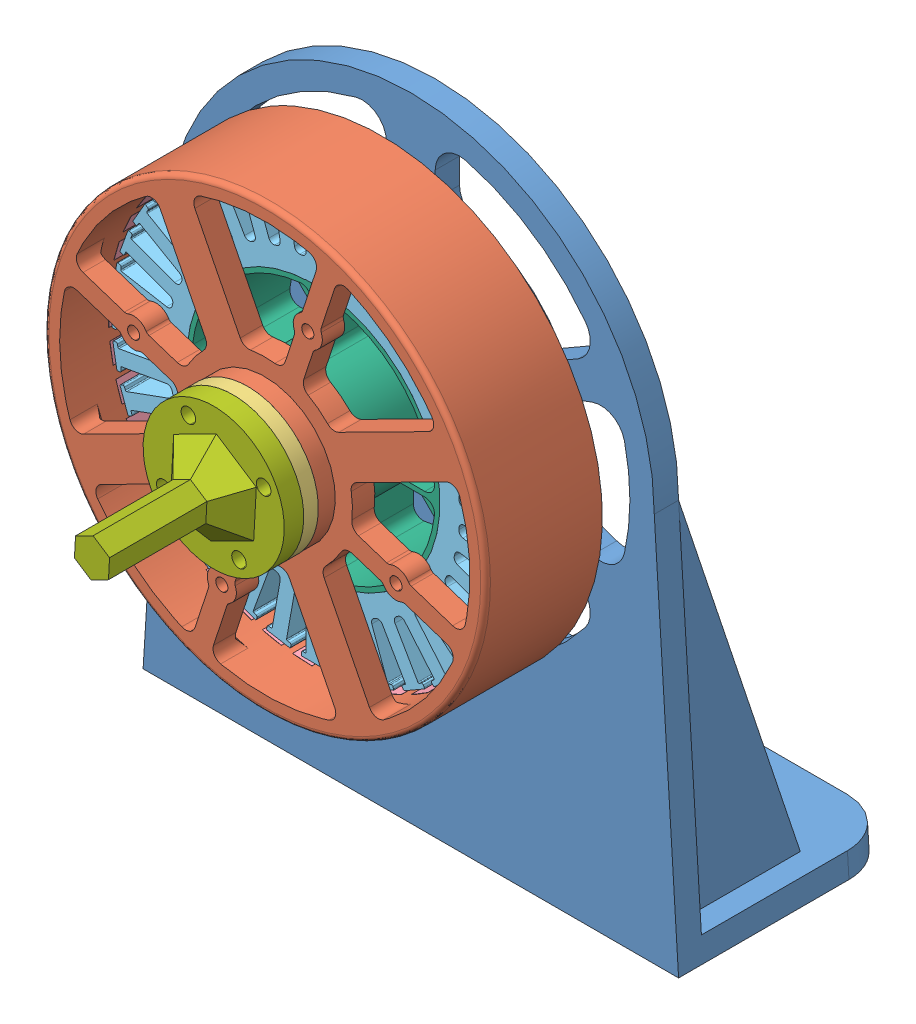
SolidWorks assembly Test Stand, configuration Default. Lengths in mm.
Overall size (130.18 145.09 110.5).
12 component instances, 11 part files, 11 mates.
Components (placement in the parent):
- Encoder Support-1: Encoder Support [Default] at (-20.1423 79.5414 128.0722) size (110 130 45)
- A12 Motor-1: A12 Motor [Default] at (-83.1923 26.4948 102.3607) x (-0.14303 0.989718 0) z (0.989718 0.14303 0) size (114.92 36.5 114.92)
  - Rotor-1: Rotor [Default] at (43.4831 60.7114 69.9891) x (0.31946 0 0.9476) z (0.9476 0 -0.31946) size (90.7 27.5 90.7)
  - Shaft-1: Shaft [Default] at (95.9137 0.9 6.4258) x (0.31946 0 0.9476) z (-0.9476 0 0.31946) size (29 32 29)
  - Magnets-1: Magnets [Default] at (-3.6016 -6.4704 0.3207) x (1 0 0) z (0 0 1) size (86.25 13 86.23)
  - Stator-1: Stator [Default] at (43.4831 37.7114 69.9891) x (0.14303 0 -0.989718) z (0.989718 0 0.14303) size (83 13 83)
  - Middle-2: Middle [Default] at (43.4831 37.7114 69.9891) x (-0.14303 0 0.989718) z (0 -1 0) size (58 58 24)
  - Cap-1: Cap [Default] at (95.9137 35.2114 6.4258) x (-0.31946 0 -0.9476) z (0 -1 0) size (16 16 5.5) (hidden)
- Crank-1: Crank [Default] at (-90.5512 122.3414 169.5722) x (0.892165 0.451711 0) z (0 0 1) size (29 29 29)
- Magnet Holder-1: Magnet Holder [Default] at (-4.9839 -1.4492 137.5722) x (0.932001 -0.362456 0) z (0 0 -1) size (14 14 18.5)
- Encoder-1: Encoder [Default] at (-20.1423 79.5414 118.8722) x (0.609347 0.792904 0) z (0.792904 -0.609347 0) size (23 3.2 23)
- Magnet-1: Magnet [Default] at (-20.1423 79.5414 123.0722) x (0 1 0) z (1 0 0) size (5 2 5)
Mates (geometry in assembly coordinates):
- Concentric1: concentric: cylinder of assembly; cylinder of assembly; cylinder of Encoder Support-1 through (-20.1423 79.5414 94.131) axis (0 0 1) radius 8.5; cylinder of A12 Motor-1/Shaft-1 through (-20.1423 79.5414 150.5722) axis (0 0 1) radius 5.5
- Concentric2: concentric: cylinder of assembly; cylinder of assembly; cylinder of Encoder Support-1 through (-8.8286 90.8551 133.0722) axis (0 0 -1) radius 1.5; cylinder of A12 Motor-1/Middle-2 through (-8.8286 90.8551 158.0722) axis (0 0 -1) radius 1.5
- Coincident1: coincident: plane of assembly; plane of assembly; plane of Encoder Support-1 through (-20.1423 79.5414 133.0722) normal (0 0 1); plane of A12 Motor-1/Middle-2 through (-20.1423 79.5414 133.0722) normal (0 0 -1)
- Concentric4: concentric: circle of assembly; circle of assembly; circle of A12 Motor-1/Shaft-1; circle of Crank-1
- Coincident4: coincident: circle of assembly; circle of assembly; circle of A12 Motor-1/Shaft-1; circle of Crank-1
- Concentric5: concentric: cylinder of assembly; cylinder of assembly; cylinder of Encoder Support-1 through (-20.1423 79.5414 94.131) axis (0 0 1) radius 8.5; cylinder of Magnet Holder-1 through (-20.1423 79.5414 142.5722) axis (0 0 -1) radius 1.5
- Coincident5: coincident: plane of assembly; circle of assembly; plane of A12 Motor-1/Shaft-1 through (-20.1423 79.5414 137.5722) normal (0 0 -1); circle of Magnet Holder-1
- Concentric6: concentric: circle of assembly; circle of assembly; circle of Magnet Holder-1; circle of Magnet-1
- Distance2: distance = 1 mm: plane of assembly; plane of assembly; plane of Magnet-1 through (-20.1423 79.5414 123.0722) normal (0 0 -1); plane of Magnet Holder-1 through (-20.1423 79.5414 124.0722) normal (0 0 -1)
- Concentric7: concentric: cylinder of assembly; circle of assembly; cylinder of Encoder-1 through (-20.1423 79.5414 121.4722) axis (0 0 -1) radius 5; circle of Magnet-1
- Distance4: distance = 1 mm: plane of assembly; plane of assembly; plane of Encoder-1 through (-20.1423 79.5414 122.0722) normal (0 0 1); plane of Magnet-1 through (-20.1423 79.5414 123.0722) normal (0 0 -1)
